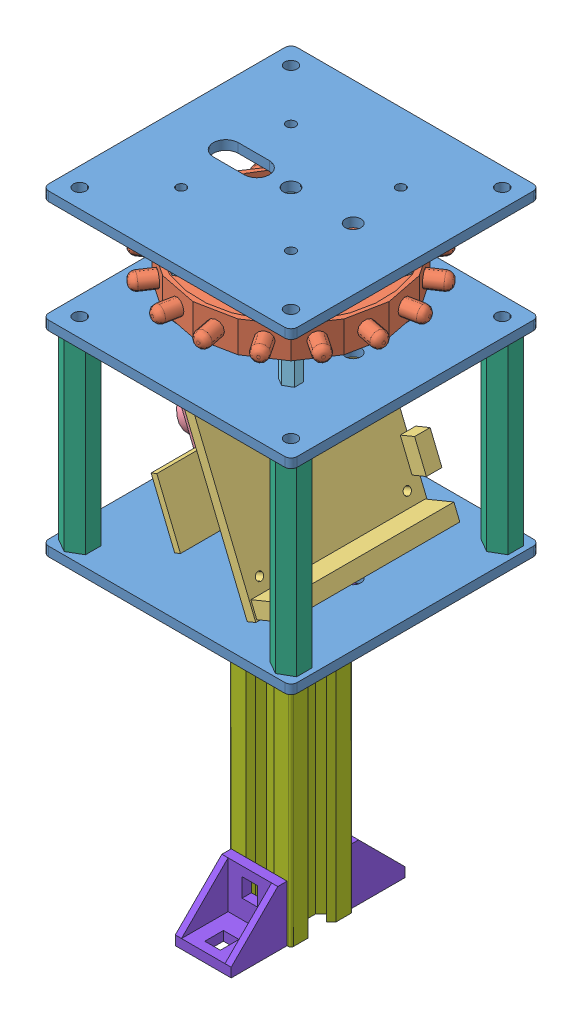
SolidWorks assembly mat_balise._camera, configuration Default. Lengths in mm.
Overall size (105.8 202 105.8).
27 component instances, 8 part files, 56 mates.
Components (placement in the parent):
- plaque_support_80x80-1: plaque_support_80x80 [Default] at (-30.8591 8.9471 28.0788) size (80 3 80)
- Recepteur_IR-1: Recepteur_IR [Default] at (9.1409 21.9471 -11.9212) x (0.707107 0 -0.707107) z (0.707107 0 0.707107) size (74.81 20 74.81)
- CMUCam3-1: CMUCam3 [Default] at (20.7931 -17.3792 -3.3111) x (-0.37973 0.925097 0) z (0 0 1) size (55.36 46 72.76)
  - Support_carte_CMUCam-1: Support_carte_CMUCam [Default] at (-32.4227 6.6898 20.4899) size (55.36 23 72.76)
  - Optique_Cmucam-1: Optique_Cmucam [Default] at (-4.5627 19.6898 -28.0601) x (0 0 1) z (-1 0 0) size (40 23 25)
- plaque_support_80x80-2: plaque_support_80x80 [Default] at (-30.8591 44.9471 28.0788) size (80 3 80)
- plaque_support_80x80-3: plaque_support_80x80 [Default] at (-30.8591 -54.0529 28.0788) size (80 3 80)
- entretoise_M3_L10-1: entretoise_M3_L10 [Default] at (-8.5367 34.9471 -29.5988) x (0.995599 0 -0.093711) z (0.093711 0 0.995599) size (5.2 10 6)
- entretoise_M3_L10-2: entretoise_M3_L10 [Default] at (26.8186 11.9471 -29.5988) size (5.2 10 6)
- entretoise_M3_L10-3: entretoise_M3_L10 [Default] at (26.8186 34.9471 5.7565) x (0.971799 0 -0.235811) z (0.235811 0 0.971799) size (5.2 10 6)
- entretoise_M3_L10-4: entretoise_M3_L10 [Default] at (26.8186 24.9471 5.7565) x (0.949818 0 0.312803) z (-0.312803 0 0.949818) size (5.2 10 6)
- entretoise_M3_L10-5: entretoise_M3_L10 [Default] at (26.8186 34.9471 -29.5988) x (0.980377 0 -0.197131) z (0.197131 0 0.980377) size (5.2 10 6)
- entretoise_M3_L10-6: entretoise_M3_L10 [Default] at (26.8186 11.9471 5.7565) size (5.2 10 6)
- entretoise_M3_L10-7: entretoise_M3_L10 [Default] at (-8.5367 24.9471 5.7565) size (5.2 10 6)
- entretoise_M3_L10-8: entretoise_M3_L10 [Default] at (-8.5367 24.9471 -29.5988) x (0.999984 0 0.005695) z (-0.005695 0 0.999984) size (5.2 10 6)
- entretoise_M3_L10-9: entretoise_M3_L10 [Default] at (26.8186 24.9471 -29.5988) x (0.952698 0 0.303917) z (-0.303917 0 0.952698) size (5.2 10 6)
- entretoise_M3_L10-10: entretoise_M3_L10 [Default] at (-8.5367 11.9471 5.7565) x (0.90842 0 -0.418058) z (0.418058 0 0.90842) size (5.2 10 6)
- entretoise_M3_L10-11: entretoise_M3_L10 [Default] at (-8.5367 34.9471 5.7565) x (0.963968 0 0.266017) z (-0.266017 0 0.963968) size (5.2 10 6)
- entretoise_M3_L10-12: entretoise_M3_L10 [Default] at (-8.5367 11.9471 -29.5988) size (5.2 10 6)
- entretoise_M5_L60-1: entretoise_M5_L60 [Default] at (43.1409 -51.0529 -45.9212) size (8.66 60 10)
- entretoise_M5_L60-2: entretoise_M5_L60 [Default] at (-24.8591 -51.0529 -45.9212) size (8.66 60 10)
- entretoise_M5_L60-3: entretoise_M5_L60 [Default] at (-24.8591 -51.0529 22.0788) size (8.66 60 10)
- entretoise_M5_L60-4: entretoise_M5_L60 [Default] at (43.1409 -51.0529 22.0788) size (8.66 60 10)
- Profilé Aluminium Rexroth 20x20 L100-1: Profilé Aluminium Rexroth 20x20 L100 [Default] at (9.1409 -154.0529 -11.9212) size (20 100 20)
- CornerXD_Rexroth_18x18-1: CornerXD_Rexroth_18x18 [Default] at (19.1409 -54.0529 -2.6712) x (0 0 -1) z (0 -1 0) size (18 18 18)
- CornerXD_Rexroth_18x18-2: CornerXD_Rexroth_18x18 [Default] at (17.8909 -154.0529 -1.9212) x (-1 0 0) z (0 1 0) size (18 18 18)
- CornerXD_Rexroth_18x18-3: CornerXD_Rexroth_18x18 [Default] at (-0.1091 -154.0529 -21.9212) x (1 0 0) z (0 1 0) size (18 18 18)
Mates (geometry in assembly coordinates):
- Coaxiale1: concentric aligned: cylinder of plaque_support_80x80-1; cylinder of Recepteur_IR-1
- Coaxiale2: concentric aligned: cylinder of plaque_support_80x80-1; cylinder of Recepteur_IR-1
- Coïncidente2: coincident: line of CMUCam3-1/Support_carte_CMUCam-1; plane of plaque_support_80x80-3 through (-30.8591 -51.0529 -51.9212) normal (0 1 0)
- Distance1: distance = 25 mm: line of CMUCam3-1/Support_carte_CMUCam-1; line of plaque_support_80x80-3
- Coïncidente5: coincident aligned: plane of plaque_support_80x80-1 through (-30.8591 11.9471 28.0788) normal (-1 0 0); plane of plaque_support_80x80-3 through (-30.8591 -51.0529 28.0788) normal (-1 0 0)
- Coïncidente6: coincident aligned: plane of plaque_support_80x80-1 through (-30.8591 11.9471 28.0788) normal (0 0 1); plane of plaque_support_80x80-3 through (-30.8591 -51.0529 28.0788) normal (0 0 1)
- Coïncidente7: coincident aligned: plane of plaque_support_80x80-1 through (-30.8591 11.9471 -51.9212) normal (0 0 -1); plane of plaque_support_80x80-2 through (-30.8591 47.9471 -51.9212) normal (0 0 -1)
- Coïncidente8: coincident aligned: plane of plaque_support_80x80-1 through (-30.8591 11.9471 28.0788) normal (-1 0 0); plane of plaque_support_80x80-2 through (-30.8591 47.9471 28.0788) normal (-1 0 0)
- Distance2: distance = 12 mm aligned: plane of CMUCam3-1/Support_carte_CMUCam-1 through (24.1409 -51.0529 -39.9212) normal (0 0 -1); plane of plaque_support_80x80-3 through (-30.8591 -51.0529 -51.9212) normal (0 0 -1)
- Coïncidente11: coincident anti-aligned: plane of plaque_support_80x80-1 through (-30.8591 11.9471 -51.9212) normal (0 1 0); plane of entretoise_M3_L10-10 through (-9.7909 11.9471 3.0312) normal (0 -1 0)
- Coïncidente12: coincident anti-aligned: plane of plaque_support_80x80-1 through (-30.8591 11.9471 -51.9212) normal (0 1 0); plane of entretoise_M3_L10-6 through (26.8186 11.9471 2.7565) normal (0 -1 0)
- Coïncidente13: coincident anti-aligned: plane of plaque_support_80x80-1 through (-30.8591 11.9471 -51.9212) normal (0 1 0); plane of entretoise_M3_L10-2 through (26.8186 11.9471 -32.5988) normal (0 -1 0)
- Coïncidente14: coincident anti-aligned: plane of plaque_support_80x80-1 through (-30.8591 11.9471 -51.9212) normal (0 1 0); plane of entretoise_M3_L10-12 through (-8.5367 11.9471 -32.5988) normal (0 -1 0)
- Coaxiale3: concentric aligned: cylinder of plaque_support_80x80-1; cylinder of entretoise_M3_L10-12
- Coaxiale4: concentric aligned: cylinder of plaque_support_80x80-1; cylinder of entretoise_M3_L10-10
- Coaxiale5: concentric aligned: cylinder of plaque_support_80x80-1; cylinder of entretoise_M3_L10-2
- Coaxiale6: concentric aligned: cylinder of plaque_support_80x80-1; cylinder of entretoise_M3_L10-6
- Coïncidente15: coincident anti-aligned: plane of Recepteur_IR-1 through (-33.8573 21.9471 -20.4741) normal (0 -1 0); plane of entretoise_M3_L10-12 through (-8.5367 21.9471 -32.5988) normal (0 1 0)
- Coïncidente16: coincident anti-aligned: plane of Recepteur_IR-1 through (9.1409 24.9471 -11.9212) normal (0 1 0); plane of entretoise_M3_L10-4 through (27.757 24.9471 2.907) normal (0 -1 0)
- Coïncidente17: coincident anti-aligned: plane of Recepteur_IR-1 through (9.1409 24.9471 -11.9212) normal (0 1 0); plane of entretoise_M3_L10-9 through (27.7304 24.9471 -32.4569) normal (0 -1 0)
- Coïncidente18: coincident anti-aligned: plane of Recepteur_IR-1 through (9.1409 24.9471 -11.9212) normal (0 1 0); plane of entretoise_M3_L10-7 through (-8.5367 24.9471 2.7565) normal (0 -1 0)
- Coïncidente19: coincident anti-aligned: plane of Recepteur_IR-1 through (9.1409 24.9471 -11.9212) normal (0 1 0); plane of entretoise_M3_L10-8 through (-8.5196 24.9471 -32.5988) normal (0 -1 0)
- Coaxiale7: concentric aligned: cylinder of Recepteur_IR-1; cylinder of entretoise_M3_L10-8
- Coaxiale8: concentric aligned: cylinder of Recepteur_IR-1; cylinder of entretoise_M3_L10-9
- Coaxiale9: concentric aligned: cylinder of Recepteur_IR-1; cylinder of entretoise_M3_L10-4
- Coaxiale10: concentric aligned: cylinder of Recepteur_IR-1; cylinder of entretoise_M3_L10-7
- Coïncidente20: coincident anti-aligned: plane of plaque_support_80x80-2 through (-30.8591 44.9471 -51.9212) normal (0 -1 0); plane of entretoise_M3_L10-5 through (26.2272 44.9471 -32.54) normal (0 1 0)
- Coïncidente21: coincident anti-aligned: plane of plaque_support_80x80-2 through (-30.8591 44.9471 -51.9212) normal (0 -1 0); plane of entretoise_M3_L10-3 through (26.1112 44.9471 2.8411) normal (0 1 0)
- Coïncidente22: coincident anti-aligned: plane of plaque_support_80x80-2 through (-30.8591 44.9471 -51.9212) normal (0 -1 0); plane of entretoise_M3_L10-11 through (-7.7387 44.9471 2.8646) normal (0 1 0)
- Coïncidente23: coincident anti-aligned: plane of plaque_support_80x80-2 through (-30.8591 44.9471 -51.9212) normal (0 -1 0); plane of entretoise_M3_L10-1 through (-8.8179 44.9471 -32.5856) normal (0 1 0)
- Coaxiale11: concentric aligned: cylinder of plaque_support_80x80-2; cylinder of entretoise_M3_L10-5
- Coaxiale12: concentric aligned: cylinder of plaque_support_80x80-2; cylinder of entretoise_M3_L10-3
- Coaxiale13: concentric aligned: cylinder of plaque_support_80x80-2; cylinder of entretoise_M3_L10-11
- Coaxiale14: concentric aligned: cylinder of plaque_support_80x80-2; cylinder of entretoise_M3_L10-1
- Coïncidente24: coincident anti-aligned: plane of entretoise_M3_L10-7 through (-8.5367 34.9471 2.7565) normal (0 1 0); plane of entretoise_M3_L10-11 through (-7.7387 34.9471 2.8646) normal (0 -1 0)
- Coïncidente25: coincident anti-aligned: plane of plaque_support_80x80-3 through (-30.8591 -51.0529 -51.9212) normal (0 1 0); plane of entretoise_M5_L60-3 through (-24.8591 -51.0529 17.0788) normal (0 -1 0)
- Coïncidente26: coincident anti-aligned: plane of entretoise_M5_L60-4 through (43.1409 -51.0529 17.0788) normal (0 -1 0); plane of plaque_support_80x80-3 through (-30.8591 -51.0529 -51.9212) normal (0 1 0)
- Coïncidente27: coincident anti-aligned: plane of plaque_support_80x80-3 through (-30.8591 -51.0529 -51.9212) normal (0 1 0); plane of entretoise_M5_L60-1 through (43.1409 -51.0529 -50.9212) normal (0 -1 0)
- Coïncidente28: coincident anti-aligned: plane of plaque_support_80x80-3 through (-30.8591 -51.0529 -51.9212) normal (0 1 0); plane of entretoise_M5_L60-2 through (-24.8591 -51.0529 -50.9212) normal (0 -1 0)
- Coaxiale15: concentric aligned: cylinder of plaque_support_80x80-3; cylinder of entretoise_M5_L60-2
- Coaxiale16: concentric aligned: cylinder of plaque_support_80x80-3; cylinder of entretoise_M5_L60-3
- Coaxiale17: concentric aligned: cylinder of plaque_support_80x80-3; cylinder of entretoise_M5_L60-1
- Coaxiale18: concentric aligned: cylinder of plaque_support_80x80-3; cylinder of entretoise_M5_L60-4
- Coïncidente29: coincident anti-aligned: plane of plaque_support_80x80-1 through (-30.8591 8.9471 -51.9212) normal (0 -1 0); plane of entretoise_M5_L60-3 through (-24.8591 8.9471 17.0788) normal (0 1 0)
- Coaxiale19: concentric aligned: cylinder of plaque_support_80x80-3; cylinder of Profilé Aluminium Rexroth 20x20 L100-1
- Coïncidente30: coincident anti-aligned: plane of plaque_support_80x80-3 through (-30.8591 -54.0529 -51.9212) normal (0 -1 0); plane of Profilé Aluminium Rexroth 20x20 L100-1 through (9.1409 -54.0529 -15.9212) normal (0 1 0)
- Parallèle1: parallel aligned: plane of plaque_support_80x80-3 through (-30.8591 -51.0529 28.0788) normal (-1 0 0); plane of Profilé Aluminium Rexroth 20x20 L100-1 through (-0.8591 -54.0529 -16.4212) normal (-1 0 0)
- Coïncidente32: coincident anti-aligned: plane of Profilé Aluminium Rexroth 20x20 L100-1 through (19.1409 -54.0529 -7.4212) normal (1 0 0); plane of CornerXD_Rexroth_18x18-1 through (19.1409 -57.0529 -2.6712) normal (-1 0 0)
- Coïncidente33: coincident anti-aligned: plane of plaque_support_80x80-3 through (-30.8591 -54.0529 -51.9212) normal (0 -1 0); plane of CornerXD_Rexroth_18x18-1 through (37.1409 -54.0529 -2.6712) normal (0 1 0)
- Coïncidente35: coincident: line of Profilé Aluminium Rexroth 20x20 L100-1; plane of CornerXD_Rexroth_18x18-1 through (19.1409 -57.0529 -2.6712) normal (0 0 1)
- Coïncidente36: coincident aligned: plane of CornerXD_Rexroth_18x18-2 through (17.8909 -154.0529 16.0788) normal (0 -1 0); plane of Profilé Aluminium Rexroth 20x20 L100-1 through (9.1409 -154.0529 -15.9212) normal (0 -1 0)
- Coïncidente37: coincident anti-aligned: plane of CornerXD_Rexroth_18x18-2 through (17.8909 -151.0529 -1.9212) normal (0 0 -1); plane of Profilé Aluminium Rexroth 20x20 L100-1 through (4.6409 -54.0529 -1.9212) normal (0 0 1)
- Coïncidente38: coincident aligned: plane of CornerXD_Rexroth_18x18-3 through (-0.1091 -154.0529 -39.9212) normal (0 -1 0); plane of Profilé Aluminium Rexroth 20x20 L100-1 through (9.1409 -154.0529 -15.9212) normal (0 -1 0)
- Coïncidente39: coincident anti-aligned: plane of Profilé Aluminium Rexroth 20x20 L100-1 through (13.6409 -54.0529 -21.9212) normal (0 0 -1); plane of CornerXD_Rexroth_18x18-3 through (-0.1091 -151.0529 -21.9212) normal (0 0 1)
- Coïncidente40: coincident aligned: plane of CornerXD_Rexroth_18x18-2 through (-0.1091 -151.0529 -1.9212) normal (-1 0 0); plane of CornerXD_Rexroth_18x18-3 through (-0.1091 -151.0529 -21.9212) normal (-1 0 0)
- Coïncidente41: coincident aligned: line of Profilé Aluminium Rexroth 20x20 L100-1; line of CornerXD_Rexroth_18x18-2
